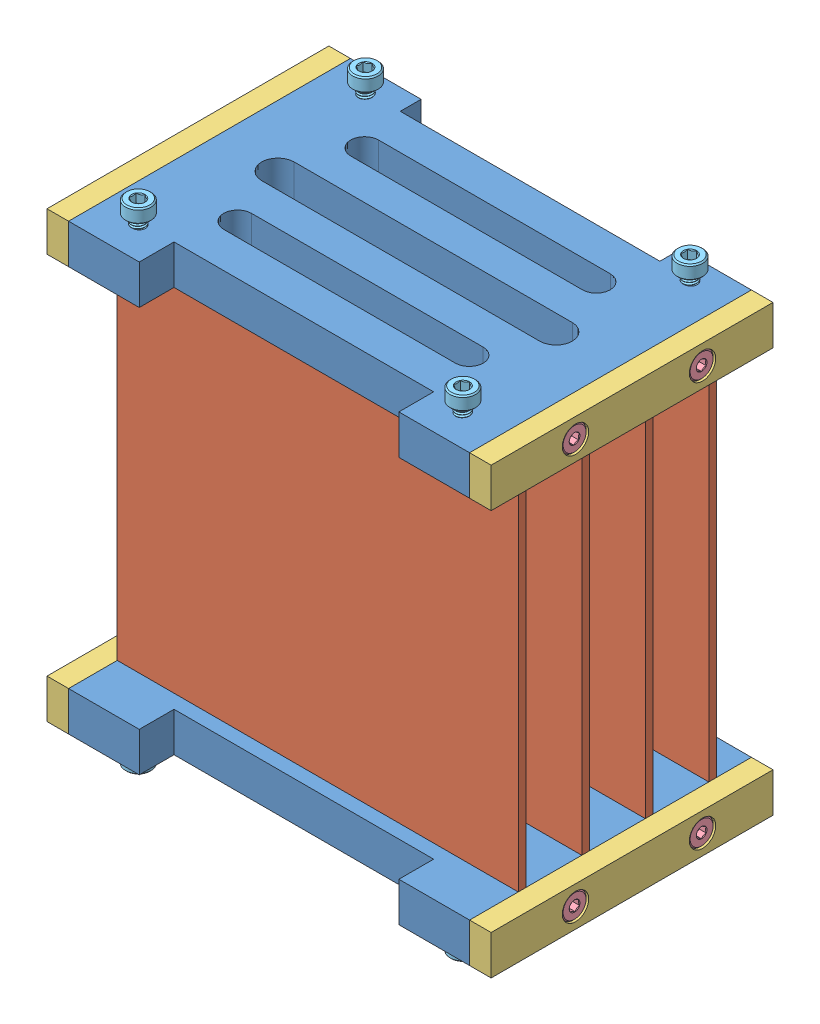
SolidWorks assembly STACK_SHELVES_ASSEMBLY, configuration Default. Lengths in mm.
Overall size (95.8 106.09 60.8).
26 component instances, 5 part files, 36 mates.
Components (placement in the parent):
- PCB_SHELF-1: PCB_SHELF [Default] at (-4.1696 1.9377 23.7027) x (0 1 0) z (1 0 0) size (8.5 60.8 86.5)
- FAKE_PCB-1: FAKE_PCB [Default] at (82.3304 4.4377 31.2027) x (0 1 0) z (1 0 0) size (91 1.7 86.5)
- FAKE_PCB-2: FAKE_PCB [Default] at (82.3304 4.4377 44.9027) x (0 1 0) z (1 0 0) size (91 1.7 86.5)
- FAKE_PCB-3: FAKE_PCB [Default] at (82.3304 4.4377 58.6027) x (0 1 0) z (1 0 0) size (91 1.7 86.5)
- FAKE_PCB-4: FAKE_PCB [Default] at (82.3304 4.3377 72.3027) x (0 1 0) z (1 0 0) size (91 1.7 86.5)
- PCB_SHELF-2: PCB_SHELF [Default] at (82.3304 97.7377 23.7027) x (0 -1 0) z (-1 0 0) size (8.5 60.8 86.5)
- PCB_SHELF_ENDS-1: PCB_SHELF_ENDS [Default] at (-4.1696 97.7377 84.5027) x (0 -1 0) z (-1 0 0) size (8.5 60.8 4.65)
- PCB_SHELF_ENDS-2: PCB_SHELF_ENDS [Default] at (-4.1696 10.4377 84.5027) x (0 -1 0) z (-1 0 0) size (8.5 60.8 4.65)
- PCB_SHELF_ENDS-3: PCB_SHELF_ENDS [Default] at (82.3304 89.2377 84.5027) x (0 1 0) z (1 0 0) size (8.5 60.8 4.65)
- PCB_SHELF_ENDS-4: PCB_SHELF_ENDS [Default] at (82.3304 1.9377 84.5027) x (0 1 0) z (1 0 0) size (8.5 60.8 4.65)
- M3_LP_6MM_90666A103_TYPE 316 SS LOW PROFILE SOCKET HEAD CAP SCREW-1: M3_LP_6MM_90666A103_TYPE 316 SS LOW PROFILE SOCKET HEAD CAP SCREW [90666A103] at (78.7804 6.1877 66.3027) x (0 -0.137884 0.990448) z (-1 0 0) size (5.5 5.5 8.16)
- M3_6MM_91292A111_TYPE 18-8 SS SOCKET HEAD CAP SCREW-1: M3_6MM_91292A111_TYPE 18-8 SS SOCKET HEAD CAP SCREW [91292A111] at (74.0804 93.7377 77.7027) x (0.999989 0 -0.00475) z (0 -1 0) size (5.5 5.5 9.19)
- M3_LP_6MM_90666A103_TYPE 316 SS LOW PROFILE SOCKET HEAD CAP SCREW-9: M3_LP_6MM_90666A103_TYPE 316 SS LOW PROFILE SOCKET HEAD CAP SCREW [90666A103] at (78.7804 6.1877 38.9027) x (0 0 1) z (-1 0 0) size (5.5 5.5 8.16)
- M3_LP_6MM_90666A103_TYPE 316 SS LOW PROFILE SOCKET HEAD CAP SCREW-3: M3_LP_6MM_90666A103_TYPE 316 SS LOW PROFILE SOCKET HEAD CAP SCREW [90666A103] at (78.7804 93.4877 66.3027) x (0 0.137884 0.990448) z (-1 0 0) size (5.5 5.5 8.16)
- M3_LP_6MM_90666A103_TYPE 316 SS LOW PROFILE SOCKET HEAD CAP SCREW-5: M3_LP_6MM_90666A103_TYPE 316 SS LOW PROFILE SOCKET HEAD CAP SCREW [90666A103] at (-0.6196 6.1877 66.3027) x (0 -0.137884 0.990448) z (1 0 0) size (5.5 5.5 8.16)
- M3_LP_6MM_90666A103_TYPE 316 SS LOW PROFILE SOCKET HEAD CAP SCREW-7: M3_LP_6MM_90666A103_TYPE 316 SS LOW PROFILE SOCKET HEAD CAP SCREW [90666A103] at (-0.6196 93.4877 66.3027) x (0 0.137884 0.990448) z (1 0 0) size (5.5 5.5 8.16)
- M3_6MM_91292A111_TYPE 18-8 SS SOCKET HEAD CAP SCREW-3: M3_6MM_91292A111_TYPE 18-8 SS SOCKET HEAD CAP SCREW [91292A111] at (4.0804 93.7377 77.7027) x (-0.999989 0 -0.00475) z (0 -1 0) size (5.5 5.5 9.19)
- M3_6MM_91292A111_TYPE 18-8 SS SOCKET HEAD CAP SCREW-5: M3_6MM_91292A111_TYPE 18-8 SS SOCKET HEAD CAP SCREW [91292A111] at (74.0804 5.9377 77.7027) x (0.999989 0 -0.00475) z (0 1 0) size (5.5 5.5 9.19)
- M3_6MM_91292A111_TYPE 18-8 SS SOCKET HEAD CAP SCREW-7: M3_6MM_91292A111_TYPE 18-8 SS SOCKET HEAD CAP SCREW [91292A111] at (4.0804 5.9377 77.7027) x (-0.999989 0 -0.00475) z (0 1 0) size (5.5 5.5 9.19)
- M3_LP_6MM_90666A103_TYPE 316 SS LOW PROFILE SOCKET HEAD CAP SCREW-10: M3_LP_6MM_90666A103_TYPE 316 SS LOW PROFILE SOCKET HEAD CAP SCREW [90666A103] at (78.7804 93.4877 38.9027) x (0 0 1) z (-1 0 0) size (5.5 5.5 8.16)
- M3_LP_6MM_90666A103_TYPE 316 SS LOW PROFILE SOCKET HEAD CAP SCREW-11: M3_LP_6MM_90666A103_TYPE 316 SS LOW PROFILE SOCKET HEAD CAP SCREW [90666A103] at (-0.6196 6.1877 38.9027) x (0 0 1) z (1 0 0) size (5.5 5.5 8.16)
- M3_LP_6MM_90666A103_TYPE 316 SS LOW PROFILE SOCKET HEAD CAP SCREW-12: M3_LP_6MM_90666A103_TYPE 316 SS LOW PROFILE SOCKET HEAD CAP SCREW [90666A103] at (-0.6196 93.4877 38.9027) x (0 0 1) z (1 0 0) size (5.5 5.5 8.16)
- M3_6MM_91292A111_TYPE 18-8 SS SOCKET HEAD CAP SCREW-9: M3_6MM_91292A111_TYPE 18-8 SS SOCKET HEAD CAP SCREW [91292A111] at (74.0804 93.7377 28.7027) x (-1 0 0) z (0 -1 0) size (5.5 5.5 9.19)
- M3_6MM_91292A111_TYPE 18-8 SS SOCKET HEAD CAP SCREW-10: M3_6MM_91292A111_TYPE 18-8 SS SOCKET HEAD CAP SCREW [91292A111] at (4.0804 93.7377 28.7027) x (1 0 0) z (0 -1 0) size (5.5 5.5 9.19)
- M3_6MM_91292A111_TYPE 18-8 SS SOCKET HEAD CAP SCREW-11: M3_6MM_91292A111_TYPE 18-8 SS SOCKET HEAD CAP SCREW [91292A111] at (74.0804 5.9377 28.7027) x (-1 0 0) z (0 1 0) size (5.5 5.5 9.19)
- M3_6MM_91292A111_TYPE 18-8 SS SOCKET HEAD CAP SCREW-12: M3_6MM_91292A111_TYPE 18-8 SS SOCKET HEAD CAP SCREW [91292A111] at (4.0804 5.9377 28.7027) x (1 0 0) z (0 1 0) size (5.5 5.5 9.19)
Mates (geometry in assembly coordinates):
- Coincident10: coincident anti-aligned: plane of PCB_SHELF-1 through (82.3304 4.4377 32.9027) normal (0 1 0); plane of FAKE_PCB-1 through (82.3304 4.4377 32.9027) normal (0 -1 0)
- Coincident11: coincident anti-aligned: plane of PCB_SHELF-1 through (82.3304 4.4377 31.2027) normal (0 0 1); plane of FAKE_PCB-1 through (82.3304 4.4377 31.2027) normal (0 0 -1)
- Coincident12: coincident aligned: plane of PCB_SHELF-1 through (82.3304 1.9377 23.7027) normal (1 0 0); plane of FAKE_PCB-1 through (82.3304 95.4377 32.9027) normal (1 0 0)
- Coincident13: coincident anti-aligned: plane of PCB_SHELF-1 through (82.3304 4.4377 46.6027) normal (0 1 0); plane of FAKE_PCB-2 through (82.3304 4.4377 46.6027) normal (0 -1 0)
- Coincident14: coincident anti-aligned: plane of PCB_SHELF-1 through (82.3304 4.4377 44.9027) normal (0 0 1); plane of FAKE_PCB-2 through (82.3304 4.4377 44.9027) normal (0 0 -1)
- Coincident15: coincident aligned: plane of PCB_SHELF-1 through (-4.1696 1.9377 23.7027) normal (-1 0 0); plane of FAKE_PCB-2 through (-4.1696 4.4377 46.6027) normal (-1 0 0)
- Coincident16: coincident anti-aligned: plane of PCB_SHELF-1 through (82.3304 4.4377 60.3027) normal (0 1 0); plane of FAKE_PCB-3 through (82.3304 4.4377 60.3027) normal (0 -1 0)
- Coincident17: coincident anti-aligned: plane of PCB_SHELF-1 through (82.3304 4.4377 58.6027) normal (0 0 1); plane of FAKE_PCB-3 through (82.3304 4.4377 58.6027) normal (0 0 -1)
- Coincident18: coincident aligned: plane of PCB_SHELF-1 through (-4.1696 1.9377 23.7027) normal (-1 0 0); plane of FAKE_PCB-3 through (-4.1696 4.4377 60.3027) normal (-1 0 0)
- Coincident19: coincident anti-aligned: plane of PCB_SHELF-1 through (82.3304 4.3377 74.0027) normal (0 1 0); plane of FAKE_PCB-4 through (82.3304 4.3377 74.0027) normal (0 -1 0)
- Coincident20: coincident anti-aligned: plane of PCB_SHELF-1 through (82.3304 4.3377 72.3027) normal (0 0 1); plane of FAKE_PCB-4 through (82.3304 4.3377 72.3027) normal (0 0 -1)
- Coincident21: coincident aligned: plane of PCB_SHELF-1 through (-4.1696 1.9377 23.7027) normal (-1 0 0); plane of FAKE_PCB-4 through (-4.1696 4.3377 74.0027) normal (-1 0 0)
- Coincident22: coincident anti-aligned: plane of FAKE_PCB-4 through (-4.1696 95.3377 74.0027) normal (0 1 0); plane of PCB_SHELF-2 through (-4.1696 95.3377 74.0027) normal (0 -1 0)
- Coincident23: coincident aligned: plane of FAKE_PCB-4 through (82.3304 95.3377 74.0027) normal (1 0 0); plane of PCB_SHELF-2 through (82.3304 97.7377 23.7027) normal (1 0 0)
- Coincident24: coincident aligned: plane of FAKE_PCB-1 through (82.3304 95.4377 32.9027) normal (1 0 0); plane of PCB_SHELF-2 through (82.3304 97.7377 23.7027) normal (1 0 0)
- Coincident25: coincident anti-aligned: plane of FAKE_PCB-1 through (82.3304 4.4377 32.9027) normal (0 0 1); plane of PCB_SHELF-2 through (-4.1696 89.2377 32.9027) normal (0 0 -1)
- Concentric1: concentric aligned: cylinder of PCB_SHELF-1 through (82.3304 6.1877 66.3027) axis (1 0 0) radius 1.25; cylinder of PCB_SHELF_ENDS-4 through (86.9804 6.1877 66.3027) axis (1 0 0) radius 1.5
- Coincident26: coincident anti-aligned: plane of PCB_SHELF-1 through (82.3304 1.9377 23.7027) normal (1 0 0); plane of PCB_SHELF_ENDS-4 through (82.3304 1.9377 84.5027) normal (-1 0 0)
- Concentric2: concentric aligned: cylinder of PCB_SHELF-1 through (82.3304 6.1877 38.9027) axis (1 0 0) radius 1.25; cylinder of PCB_SHELF_ENDS-4 through (86.9804 6.1877 38.9027) axis (1 0 0) radius 1.5
- Coincident27: coincident anti-aligned: plane of PCB_SHELF-2 through (82.3304 97.7377 23.7027) normal (1 0 0); plane of PCB_SHELF_ENDS-3 through (82.3304 89.2377 84.5027) normal (-1 0 0)
- Concentric3: concentric aligned: cylinder of PCB_SHELF-2 through (82.3304 93.4877 66.3027) axis (1 0 0) radius 1.25; cylinder of PCB_SHELF_ENDS-3 through (86.9804 93.4877 66.3027) axis (1 0 0) radius 1.5
- Concentric4: concentric aligned: cylinder of PCB_SHELF-2 through (82.3304 93.4877 38.9027) axis (1 0 0) radius 1.25; cylinder of PCB_SHELF_ENDS-3 through (86.9804 93.4877 38.9027) axis (1 0 0) radius 1.5
- Coincident28: coincident anti-aligned: plane of PCB_SHELF-1 through (-4.1696 1.9377 23.7027) normal (-1 0 0); plane of PCB_SHELF_ENDS-2 through (-4.1696 10.4377 84.5027) normal (1 0 0)
- Concentric5: concentric aligned: cylinder of PCB_SHELF-1 through (-4.1696 6.1877 66.3027) axis (-1 0 0) radius 1.25; cylinder of PCB_SHELF_ENDS-2 through (-8.8196 6.1877 66.3027) axis (-1 0 0) radius 1.5
- Concentric6: concentric aligned: cylinder of PCB_SHELF-1 through (-4.1696 6.1877 38.9027) axis (-1 0 0) radius 1.25; cylinder of PCB_SHELF_ENDS-2 through (-8.8196 6.1877 38.9027) axis (-1 0 0) radius 1.5
- Coincident29: coincident anti-aligned: plane of PCB_SHELF-2 through (-4.1696 97.7377 23.7027) normal (-1 0 0); plane of PCB_SHELF_ENDS-1 through (-4.1696 97.7377 84.5027) normal (1 0 0)
- Concentric7: concentric aligned: cylinder of PCB_SHELF-2 through (-4.1696 93.4877 66.3027) axis (-1 0 0) radius 1.25; cylinder of PCB_SHELF_ENDS-1 through (-8.8196 93.4877 66.3027) axis (-1 0 0) radius 1.5
- Concentric8: concentric aligned: cylinder of PCB_SHELF-2 through (-4.1696 93.4877 38.9027) axis (-1 0 0) radius 1.25; cylinder of PCB_SHELF_ENDS-1 through (-8.8196 93.4877 38.9027) axis (-1 0 0) radius 1.5
- Concentric9: concentric anti-aligned: circle of PCB_SHELF_ENDS-4; circle of M3_LP_6MM_90666A103_TYPE 316 SS LOW PROFILE SOCKET HEAD CAP SCREW-1
- Coincident31: coincident anti-aligned: plane of PCB_SHELF_ENDS-4 through (84.7804 6.1877 66.3027) normal (1 0 0); plane of M3_LP_6MM_90666A103_TYPE 316 SS LOW PROFILE SOCKET HEAD CAP SCREW-1 through (84.7804 6.1877 66.3027) normal (-1 0 0)
- Concentric10: concentric anti-aligned: circle of PCB_SHELF-2; circle of M3_6MM_91292A111_TYPE 18-8 SS SOCKET HEAD CAP SCREW-1
- Distance1: distance = 2 mm anti-aligned: plane of PCB_SHELF-2 through (-4.1696 97.7377 23.7027) normal (0 1 0); plane of M3_6MM_91292A111_TYPE 18-8 SS SOCKET HEAD CAP SCREW-1 through (74.0804 99.7377 77.7027) normal (0 -1 0)
- Concentric11: concentric anti-aligned: circle of PCB_SHELF-1; circle of M3_LP_6MM_90666A103_TYPE 316 SS LOW PROFILE SOCKET HEAD CAP SCREW-9
- Coincident32: coincident anti-aligned: plane of PCB_SHELF_ENDS-4 through (84.7804 6.1877 38.9027) normal (1 0 0); plane of M3_LP_6MM_90666A103_TYPE 316 SS LOW PROFILE SOCKET HEAD CAP SCREW-9 through (84.7804 6.1877 38.9027) normal (-1 0 0)
- Concentric12: concentric anti-aligned: circle of PCB_SHELF-2; circle of M3_6MM_91292A111_TYPE 18-8 SS SOCKET HEAD CAP SCREW-9
- Distance2: distance = 2 mm anti-aligned: plane of PCB_SHELF-2 through (-4.1696 97.7377 23.7027) normal (0 1 0); plane of M3_6MM_91292A111_TYPE 18-8 SS SOCKET HEAD CAP SCREW-9 through (74.0804 99.7377 28.7027) normal (0 -1 0)
